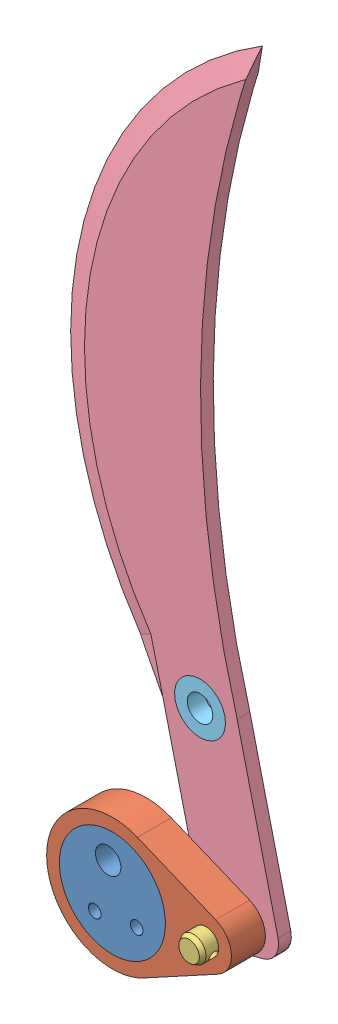
SolidWorks assembly 曲柄摇杆机构, configuration 默认. Lengths in mm.
Overall size (106.11 197.45 18).
5 component instances, 5 part files, 11 mates.
Components (placement in the parent):
- 偏心块-1: 偏心块 [默认] at (-6.0351 3.3689 21.2103) x (-0.987414 -0.158158 0) z (0 0 1) size (25 25 8)
- 连杆2-1: 连杆2 [默认] at (-6.0351 3.3689 21.2103) x (0.998537 0.054079 0) z (0 0 1) size (43.6 31 8)
- M6-16销轴-1: M6-16销轴 [GB_CONNECTING_PIECE_PIN_CPWH 6X16] at (16.0325 4.564 15.2103) x (0 0 1) z (-0.373589 -0.927594 0) size (18 10 10)
- 动刀片-1: 动刀片 [默认] at (-2.1208 41.3262 18.2103) x (0.971961 0.235142 0) z (0 0 1) size (65.62 180 3)
- 垫圈-1: 垫圈 [默认] at (6.6269 43.4424 17.2103) size (12 12 4)
Mates (geometry in assembly coordinates):
- 同心1: concentric aligned: cylinder of 偏心块-1 through (-6.0351 3.3689 29.2103) axis (0 0 -1) radius 12.5; cylinder of 连杆2-1 through (-6.0351 3.3689 29.2103) axis (0 0 -1) radius 15.5
- 重合1: coincident aligned: plane of 偏心块-1 through (-6.0351 3.3689 29.2103) normal (0 0 1); plane of 连杆2-1 through (-6.0351 3.3689 29.2103) normal (0 0 1)
- 同心2: concentric aligned: cylinder of 连杆2-1 through (16.0325 4.564 29.2103) axis (0 0 -1) radius 3; cylinder of 动刀片-1 through (16.0325 4.564 21.2103) axis (0 0 -1) radius 3
- 重合2: coincident anti-aligned: plane of 连杆2-1 through (-6.0351 3.3689 21.2103) normal (0 0 -1); plane of 动刀片-1 through (69.6234 103.598 21.2103) normal (0 0 1)
- 同心3: concentric aligned: cylinder of 连杆2-1 through (16.0325 4.564 29.2103) axis (0 0 -1) radius 3; cylinder of M6-16销轴-1 through (16.0325 4.564 -4.6197) axis (0 0 -1) radius 3
- 距离1: distance = 4 mm aligned: plane of M6-16销轴-1 through (16.0325 4.564 33.2103) normal (0 0 1); plane of 连杆2-1 through (-6.0351 3.3689 29.2103) normal (0 0 1)
- 同心4: concentric aligned: cylinder of 动刀片-1 through (6.6269 43.4424 21.2103) axis (0 0 -1) radius 6; cylinder of 垫圈-1 through (6.6269 43.4424 21.2103) axis (0 0 -1) radius 6
- 重合4: coincident aligned: plane of 动刀片-1 through (69.6234 103.598 21.2103) normal (0 0 1); plane of 垫圈-1 through (6.6269 43.4424 21.2103) normal (0 0 1)
- 角度1: planar angle = 1.387537 rad aligned: line of 动刀片-1 through (-4.1602 43.8633 21.1182) axis (0.235142 -0.971961 0); line of 连杆2-1 through (-8.0746 5.906 21.1182) axis (0.998537 0.054079 0)
- 角度2: planar angle = 1.675516 rad aligned: line of 偏心块-1 through (-6.0976 -6.4367 21.1182) axis (-0.158158 0.987414 0); line of 连杆2-1 through (-8.0746 5.906 21.1182) axis (0.998537 0.054079 0)
- 平行1: parallel: line of ? through (-26.3925 157.5038 19.6182) axis (0 -1 0)
